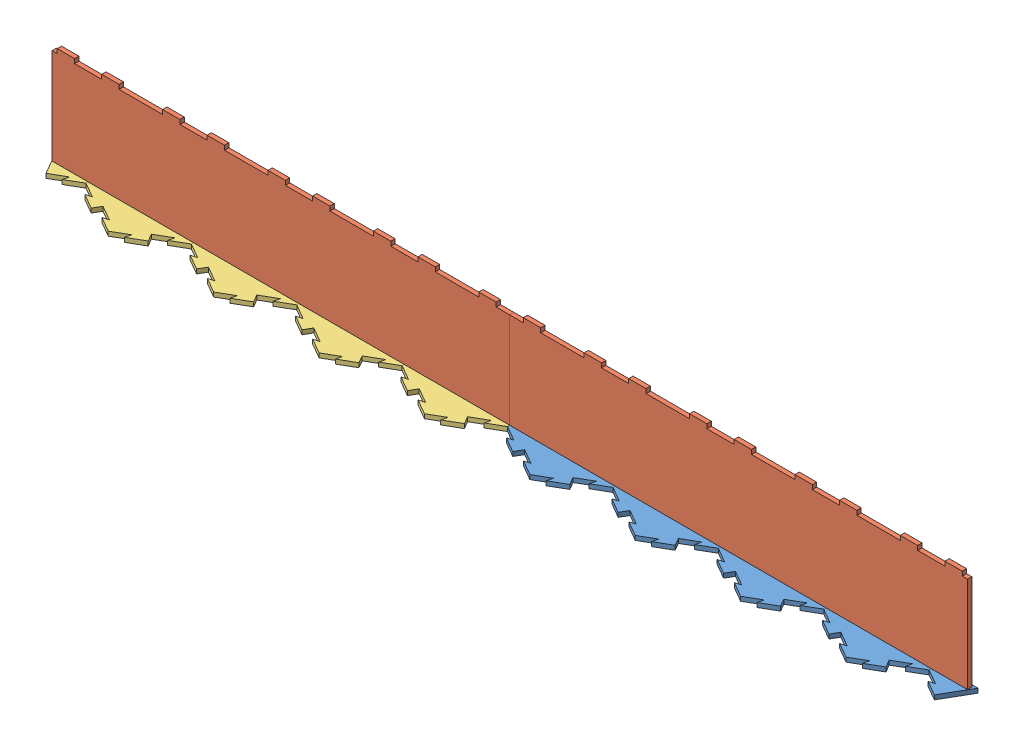
SolidWorks assembly Assem3, configuration Default. Lengths in mm.
Overall size (1349.15 152.4 88.9).
4 component instances, 3 part files, 9 mates.
Components (placement in the parent):
- border_module-1: border_module [Default] at origin size (733.23 6.35 88.9)
- Wall_seg_full-1: Wall_seg_full [Default] at (230.969 69.85 -3.175) x (-1 0 0) z (0 -1 0) size (668.78 6.35 152.4)
- border_module2-1: border_module2 [Default] at (-615.9173 0 0) size (733.23 6.35 88.9)
- Wall_seg_full-2: Wall_seg_full [Default] at (-384.9483 69.85 -9.525) x (1 0 0) z (0 -1 0) size (668.78 6.35 152.4)
Mates (geometry in assembly coordinates):
- Coincident1: coincident anti-aligned: plane of border_module-1 through (-57.15 -6.35 -9.525) normal (1 0 0); plane of Wall_seg_full-1 through (-57.15 0 -3.175) normal (-1 0 0)
- Coincident2: coincident anti-aligned: plane of border_module-1 through (-57.15 -6.35 -3.175) normal (0 0 -1); plane of Wall_seg_full-1 through (230.969 69.85 -3.175) normal (0 0 1)
- Coincident3: coincident aligned: plane of border_module-1 through (0 -6.35 0) normal (0 -1 0); plane of Wall_seg_full-1 through (591.7873 -6.35 -9.525) normal (0 -1 0)
- Coincident4: coincident anti-aligned: plane of border_module-1 through (-76.9897 -6.35 -88.9) normal (-1 0 0); plane of border_module2-1 through (-76.9897 -6.35 0) normal (1 0 0)
- Coincident5: coincident aligned: plane of border_module-1 through (-76.9897 -6.35 -12.7) normal (0 0 -1); plane of border_module2-1 through (-230.969 -6.35 -12.7) normal (0 0 -1)
- Coincident6: coincident aligned: plane of border_module-1 through (0 -6.35 0) normal (0 -1 0); plane of border_module2-1 through (-153.9793 -6.35 0) normal (0 -1 0)
- Coincident7: coincident anti-aligned: plane of border_module2-1 through (-96.8293 -6.35 -9.525) normal (-1 0 0); plane of Wall_seg_full-2 through (-96.8293 0 -9.525) normal (1 0 0)
- Coincident8: coincident anti-aligned: plane of border_module2-1 through (-122.2293 -6.35 -9.525) normal (0 0 1); plane of Wall_seg_full-2 through (-384.9483 69.85 -9.525) normal (0 0 -1)
- Coincident9: coincident aligned: plane of border_module2-1 through (-153.9793 -6.35 0) normal (0 -1 0); plane of Wall_seg_full-2 through (-745.7666 -6.35 -3.175) normal (0 -1 0)
